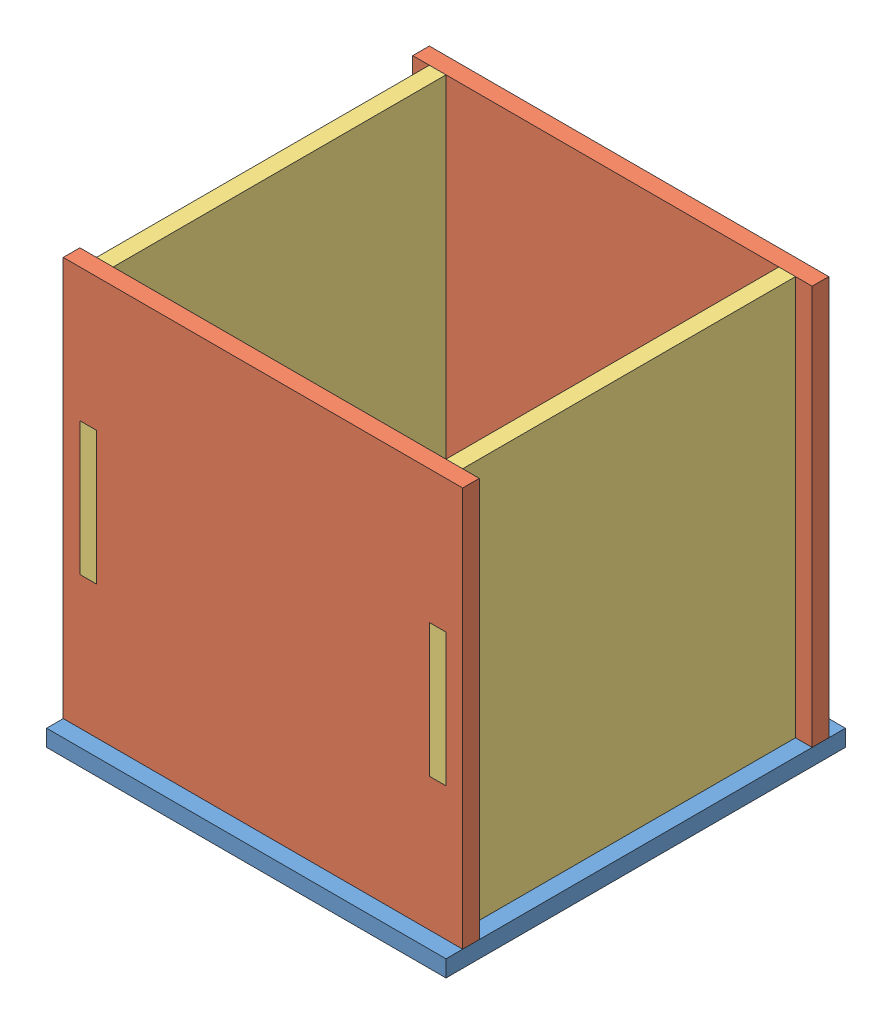
SolidWorks assembly device, configuration Default. Lengths in mm.
Overall size (152.4 158.75 152.4).
5 component instances, 3 part files, 12 mates.
Components (placement in the parent):
- base-1: base [Default] at (-21.7952 66.9064 167.0762) size (152.4 6.35 152.4)
- sidea-1: sidea [Default] at (54.4048 146.2814 21.0262) x (1 0 0) z (0 -1 0) size (152.4 6.35 158.75)
- sidea-2: sidea [Default] at (54.4048 146.2814 154.3762) x (1 0 0) z (0 -1 0) size (152.4 6.35 158.75)
- sideb-2: sideb [Default] at (117.9048 146.2814 90.8762) x (0 0 -1) z (0 -1 0) size (139.7 6.35 158.75)
- sideb-3: sideb [Default] at (-15.4452 146.2814 90.8762) x (0 0 -1) z (0 -1 0) size (139.7 6.35 158.75)
Mates (geometry in assembly coordinates):
- Coincident1: coincident: plane of base-1 through (79.8048 79.6064 21.0262) normal (-1 0 0); plane of sidea-1 through (79.8048 146.2814 27.3762) normal (1 0 0)
- Coincident2: coincident: plane of base-1 through (-21.7952 66.9064 167.0762) normal (0 -1 0); plane of sidea-1 through (54.4048 66.9064 27.3762) normal (0 -1 0)
- Coincident3: coincident: plane of base-1 through (29.0048 79.6064 27.3762) normal (0 0 -1); plane of sidea-1 through (54.4048 146.2814 27.3762) normal (0 0 1)
- Coincident4: coincident: plane of base-1 through (-21.7952 66.9064 167.0762) normal (0 -1 0); plane of sidea-2 through (54.4048 66.9064 160.7262) normal (0 -1 0)
- Coincident6: coincident: plane of base-1 through (29.0048 79.6064 160.7262) normal (1 0 0); plane of sidea-2 through (29.0048 146.2814 160.7262) normal (-1 0 0)
- Coincident7: coincident: plane of base-1 through (29.0048 79.6064 154.3762) normal (0 0 1); plane of sidea-2 through (54.4048 146.2814 154.3762) normal (0 0 -1)
- Coincident14: coincident: plane of base-1 through (124.2548 79.6064 116.2762) normal (0 0 -1); plane of sideb-2 through (130.6048 57.5591 116.2762) normal (0 0 1)
- Coincident15: coincident: plane of base-1 through (-15.4452 79.6064 116.2762) normal (0 0 -1); plane of sideb-3 through (-2.7452 66.9064 116.2762) normal (0 0 1)
- Coincident16: coincident: line of base-1 through (-15.4452 66.9064 116.2762) axis (0 0 -1); plane of sideb-3 through (-15.4452 146.2814 90.8762) normal (-1 0 0)
- Coincident17: coincident: plane of base-1 through (-21.7952 66.9064 167.0762) normal (0 -1 0); plane of sideb-3 through (-9.0952 66.9064 90.8762) normal (0 -1 0)
- Coincident18: coincident: plane of base-1 through (124.2548 79.6064 65.4762) normal (-1 0 0); plane of sideb-2 through (124.2548 146.2814 90.8762) normal (1 0 0)
- Coincident19: coincident: plane of base-1 through (-21.7952 66.9064 167.0762) normal (0 -1 0); plane of sideb-2 through (124.2548 66.9064 90.8762) normal (0 -1 0)
